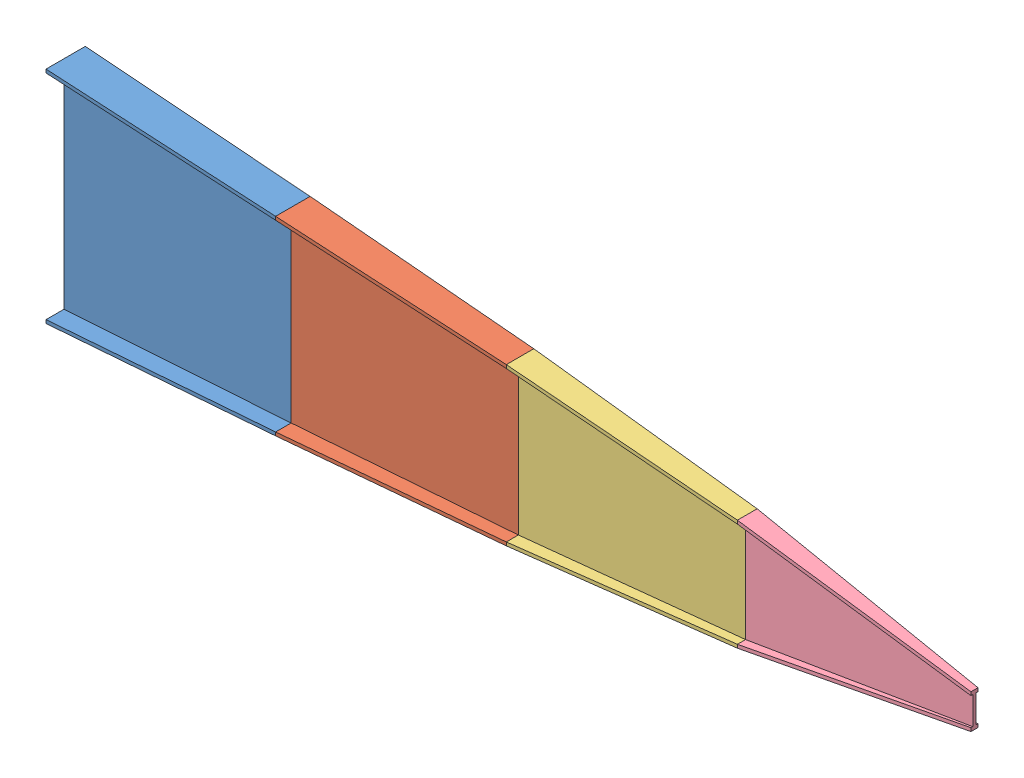
SolidWorks assembly trial_run, configuration Default. Lengths in mm.
Overall size (4000 970 173).
4 component instances, 4 part files, 9 mates.
Components (placement in the parent):
- p1-1: p1 [Default] at (-539.4321 563.4995 954.5719) size (1000 970 173)
- p2-1: p2 [Default] at (460.5679 563.4995 954.5719) size (1000 837 152)
- p3-1: p3 [Default] at (1460.5679 563.4995 954.5719) size (1000 691 121)
- p4-1: p4 [Default] at (2460.5679 563.4995 954.5719) size (1000 488 87)
Mates (geometry in assembly coordinates):
- Coincident1: coincident: point of 1-1; point of 2-1
- Coincident2: coincident: point of p2-1; point of 3-1
- Coincident3: coincident: point of p3-1; point of 4-1
- Coincident4: coincident: point of p1-1; point of p2-1
- Coincident5: coincident: point of p2-1; point of p3-1
- Coincident6: coincident: point of p3-1; point of p4-1
- Coincident7: coincident aligned: plane of p1-1 through (-539.4321 563.4995 969.5719) normal (0 0 1); plane of p2-1 through (460.5679 563.4995 969.5719) normal (0 0 1)
- Coincident8: coincident aligned: plane of p2-1 through (460.5679 563.4995 959.5719) normal (0 0 1); plane of p3-1 through (1460.5679 563.4995 959.5719) normal (0 0 1)
- Coincident9: coincident aligned: plane of p3-1 through (1460.5679 563.4995 969.5719) normal (0 0 1); plane of p4-1 through (2460.5679 563.4995 969.5719) normal (0 0 1)
